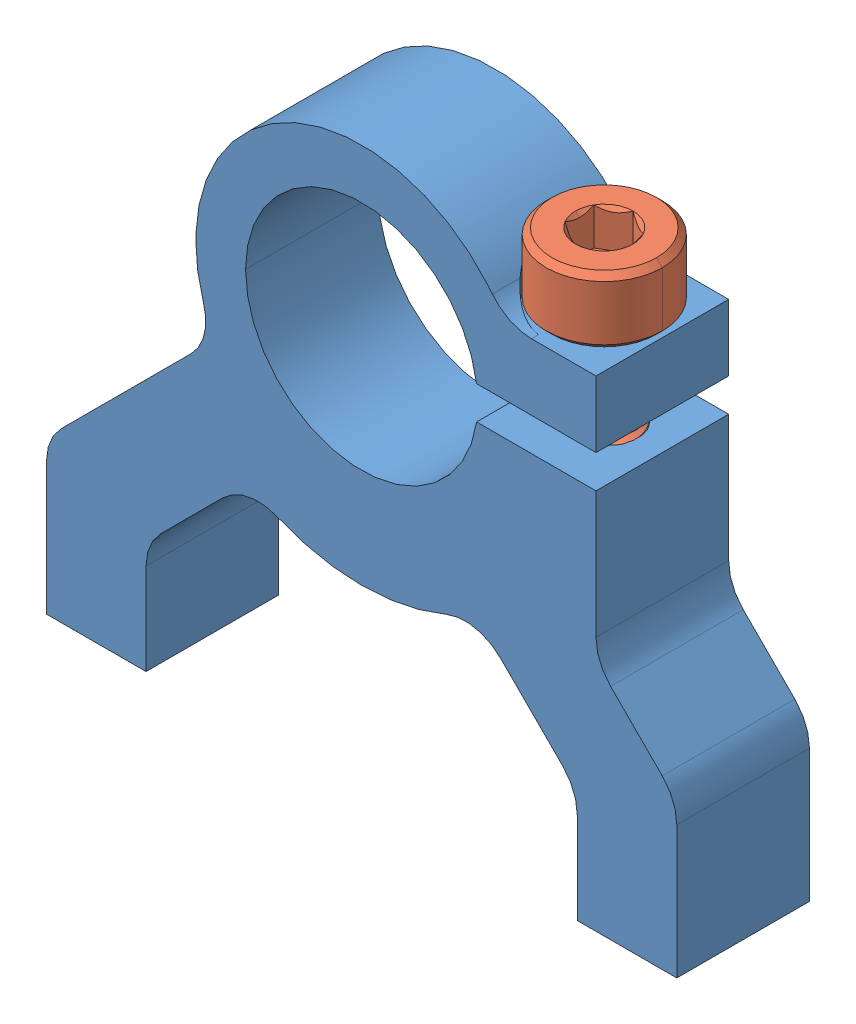
SolidWorks assembly 1400-0032-0014 assembly, configuration Default. Lengths in mm.
Overall size (38 34 8).
3 component instances, 2 part files, 0 mates.
Components (placement in the parent):
- 1400-0032-0014 assembly.STEP-1: 1400-0032-0014 assembly.STEP [Default] at origin size (38 34 8)
  - 1400-0032-0014.STEP-1: 1400-0032-0014.STEP [Default] at (-6.7355 7.0141 -0.371) size (38 34 8)
  - 2800-0004-0012_90128A207.STEP-1: 2800-0004-0012_90128A207.STEP [Default] at (3.8927 0.0141 3.629) x (1 0 0) z (0 -1 0) size (7 7 16.01)
